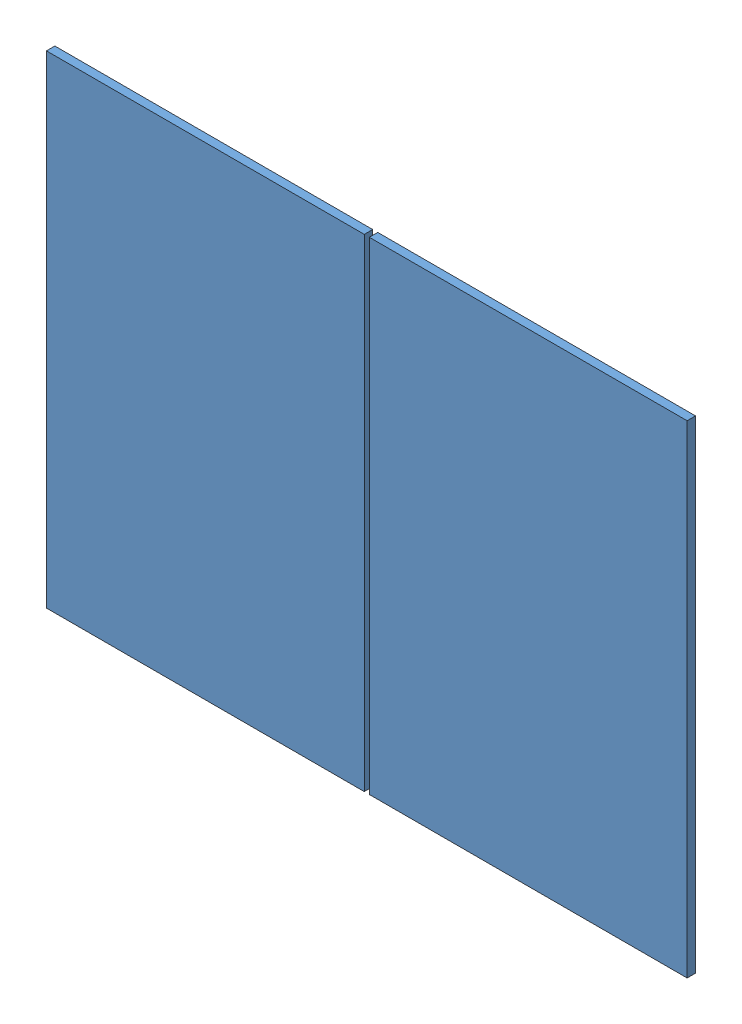
SolidWorks assembly planpanneaux, configuration Défaut. Lengths in mm.
Overall size (2286 1722 30).
2 component instances, 1 part files, 3 mates.
Components (placement in the parent):
- JkM425N-54HL4-B-1: JkM425N-54HL4-B [Défaut] at (-76.123 -83.1343 1707) size (1134 1722 30)
- JkM425N-54HL4-B-2: JkM425N-54HL4-B [Défaut] at (1075.877 -83.1343 1707) size (1134 1722 30)
Mates (geometry in assembly coordinates):
- Coïncidente1: coincident: plane of assembly; plane of JkM425N-54HL4-B-2 through (508.877 -944.1343 1737) normal (-1 0 0); plane of assembly
- Coïncidente2: coincident: plane of JkM425N-54HL4-B-1 through (-643.123 777.8657 1737) normal (0 1 0); plane of JkM425N-54HL4-B-2 through (508.877 777.8657 1737) normal (0 1 0)
- Coïncidente3: coincident aligned: plane of JkM425N-54HL4-B-1 through (-76.123 -83.1343 1707) normal (0 0 -1); plane of JkM425N-54HL4-B-2 through (1075.877 -83.1343 1707) normal (0 0 -1)
